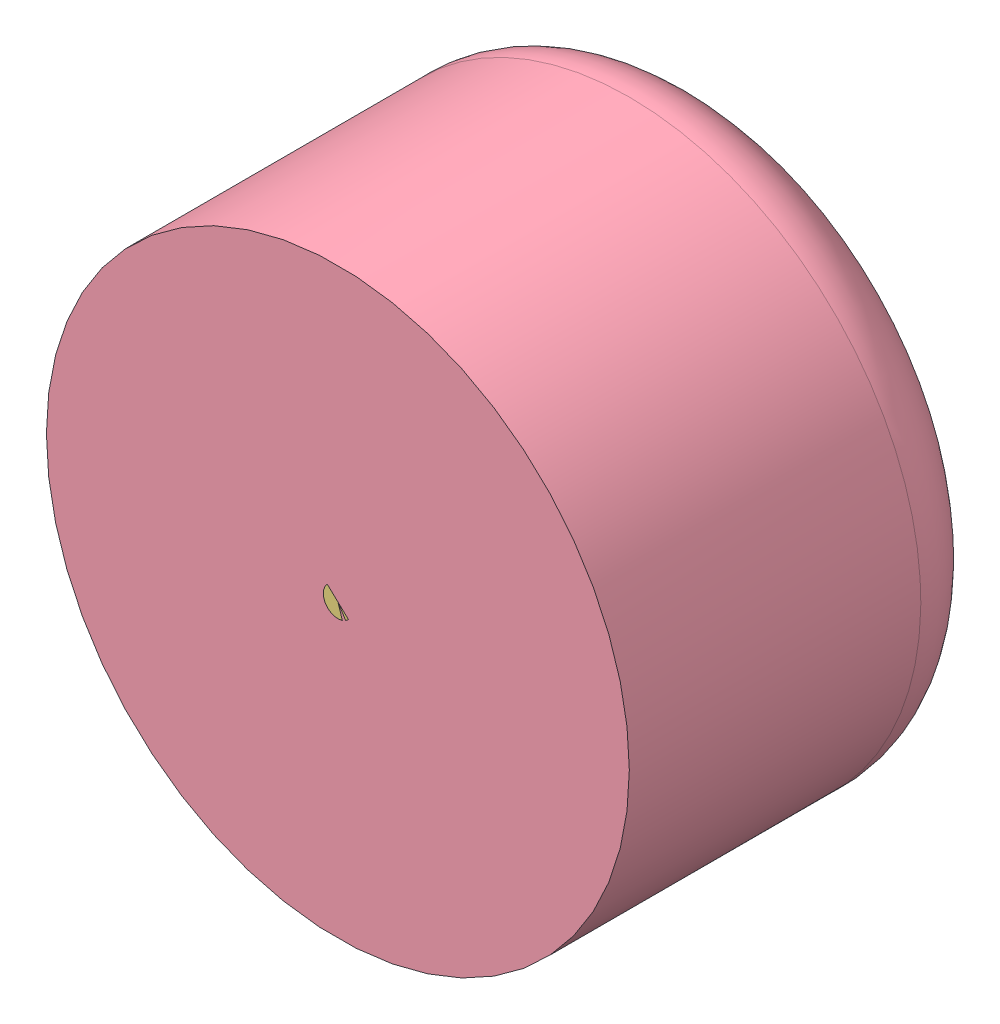
SolidWorks assembly Assem1, configuration Default. Lengths in mm.
Overall size (507.42 507.42 350).
4 component instances, 4 part files, 5 mates.
Components (placement in the parent):
- fan_impeller-3: fan_impeller [Default] at origin size (461 452.59 50)
- rotar_region-1: rotar_region [Default] at origin size (480 480 50)
- shaft-1: shaft [Default] at (0 0 50) size (25 25 200)
- tank-2: tank [Default] at origin size (507.42 507.42 350)
Mates (geometry in assembly coordinates):
- Concentric1: concentric aligned: circle of fan_impeller-3; circle of rotar_region-1
- Coincident5: coincident aligned: plane of fan_impeller-3 through (0 0 50) normal (0 0 1); plane of rotar_region-1 through (0 0 50) normal (0 0 1)
- Coincident7: coincident aligned: circle of fan_impeller-3; circle of shaft-1
- Concentric2: concentric: circle of shaft-1; circle of tank-2
- Coincident8: coincident aligned: plane of shaft-1 through (0 0 250) normal (0 0 1); plane of tank-2 through (0 0 250) normal (0 0 1)
